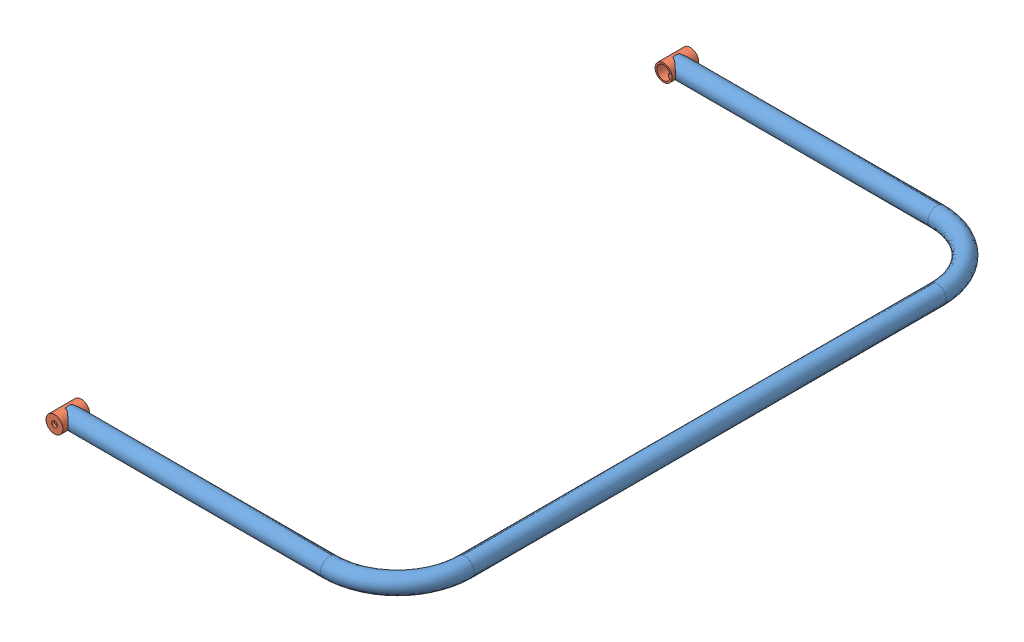
SolidWorks assembly ТП.016.04.07.00 - Дуга безопасности в сборе, configuration 00. Lengths in mm.
Overall size (511.45 27 939).
3 component instances, 2 part files, 6 mates.
Components (placement in the parent):
- ТП.016.04.07.01 - Дуга модель-1: ТП.016.04.07.01 - Дуга модель [--] at origin size (499.96 27 924)
- ТП.016.04.07.02 - Стакан оси рычага-1: ТП.016.04.07.02 - Стакан оси рычага [--] at (0 0 -5) x (0 0 -1) z (0 -1 0) size (39.5 25 25)
- ТП.016.04.07.02 - Стакан оси рычага-2: ТП.016.04.07.02 - Стакан оси рычага [--] at (0 0 -865) x (0 0 1) z (0 1 0) size (39.5 25 25)
Mates (geometry in assembly coordinates):
- Концентричный1: concentric: cylinder of ТП.016.04.07.01 - Дуга модель-1 through (0 0 995) axis (0 0 1) radius 12.5; cylinder of ТП.016.04.07.02 - Стакан оси рычага-1 through (0 0 995) axis (0 0 1) radius 12.5
- Параллельность1: parallel: plane of ТП.016.04.07.02 - Стакан оси рычага-1 through (7.5 -2.5 -10.5902) normal (0 -1 0); plane of assembly
- Расстояние1: distance = 7.5 mm: plane of ТП.016.04.07.02 - Стакан оси рычага-1 through (0 4.25 34.5) normal (0 0 1); cylinder of ТП.016.04.07.01 - Дуга модель-1 through (0 0 13.5) axis (1 0 0) radius 13.5
- Концентричный2: concentric: cylinder of ТП.016.04.07.01 - Дуга модель-1 through (0 0 -1865) axis (0 0 -1) radius 12.5; cylinder of ТП.016.04.07.02 - Стакан оси рычага-2 through (0.0994 -0.4646 -1005) axis (0 0 -1) radius 12.5
- Расстояние2: distance = 7.5 mm: cylinder of ТП.016.04.07.01 - Дуга модель-1 through (0 0 -883.5) axis (1 0 0) radius 13.5; plane of ТП.016.04.07.02 - Стакан оси рычага-2 through (0 -4.25 -904.5) normal (0 0 -1)
- Совпадение1: coincident: plane of ТП.016.04.07.02 - Стакан оси рычага-1 through (7.5 2.5 -10.5902) normal (-1 0 0); plane of ТП.016.04.07.02 - Стакан оси рычага-2 through (7.5 -2.5 -859.4098) normal (-1 0 0)
